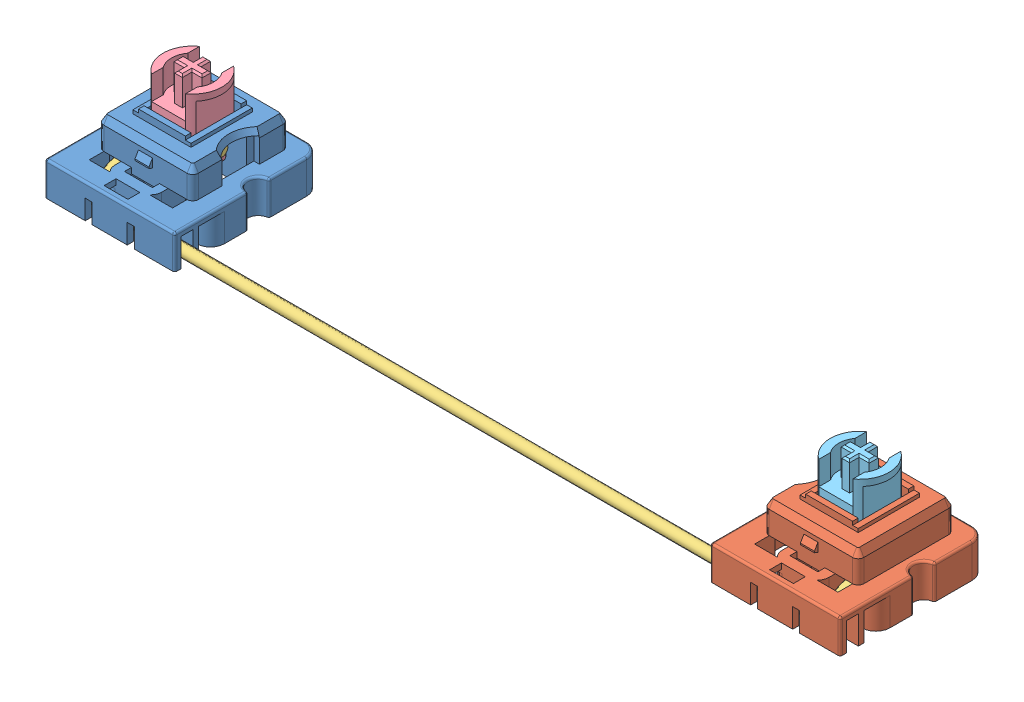
SolidWorks assembly 6u Stabilizers, configuration Default. Lengths in mm.
Overall size (113.55 14.95 20.85).
5 component instances, 5 part files, 12 mates.
Components (placement in the parent):
- 6u Stabilizer Housing Left-1: 6u Stabilizer Housing Left [Default] at (6.8702 11.4991 13.5894) size (18.55 10.05 20.85)
- 6u Stabilizer Housing Right-1: 6u Stabilizer Housing Right [Default] at (101.8702 11.4991 13.5894) size (18.55 10.05 20.85)
- Stabilizer Wire-1: Stabilizer Wire [Default] at (54.3702 9.1991 23.8394) x (1 0 0) z (0 -0.386731 0.922193) size (106 1.6 13.1)
- 6u Stabilizer Plunger Left rev.2-1: 6u Stabilizer Plunger Left rev.2 [Default] at (6.7452 18.4465 13.5894) size (8.4 10.8 6.85)
- 6u Stabilizer Plunger Right rev.2-1: 6u Stabilizer Plunger Right rev.2 [Default] at (101.9952 18.4465 13.5894) size (8.4 10.8 6.85)
Mates (geometry in assembly coordinates):
- Coincident2: coincident: plane of 6u Stabilizer Housing Left-1 through (6.8702 11.4991 13.5894) normal (0 0 1); plane of 6u Stabilizer Housing Right-1 through (101.8702 11.4991 13.5894) normal (0 0 1)
- Coincident3: coincident: plane of 6u Stabilizer Housing Left-1 through (6.8702 11.4991 13.5894) normal (0 1 0); plane of 6u Stabilizer Housing Right-1 through (101.8702 11.4991 13.5894) normal (0 1 0)
- Tangent1: tangent: plane of 6u Stabilizer Housing Left-1 through (6.8702 9.9991 13.5894) normal (0 -1 0); cylinder of Stabilizer Wire-1 through (104.9702 9.1991 23.8394) axis (-1 0 0) radius 0.8
- Tangent2: tangent: plane of 6u Stabilizer Housing Left-1 through (16.1452 -11.0727 24.6394) normal (0 0 -1); cylinder of Stabilizer Wire-1 through (104.9702 9.1991 23.8394) axis (-1 0 0) radius 0.8
- Distance1: distance = 47.5 mm: plane of 6u Stabilizer Housing Left-1 through (6.8702 11.4991 13.5894) normal (1 0 0); plane of Stabilizer Wire-1 through (54.3702 9.1991 23.8394) normal (1 0 0)
- Distance2: distance = 47.5 mm: plane of 6u Stabilizer Housing Right-1 through (101.8702 11.4991 13.5894) normal (1 0 0); plane of Stabilizer Wire-1 through (54.3702 9.1991 23.8394) normal (1 0 0)
- Coincident9: coincident: plane of 6u Stabilizer Housing Left-1 through (6.8702 11.4991 13.5894) normal (1 0 0); plane of 6u Stabilizer Plunger Left rev.2-1 through (6.8702 18.4465 13.5894) normal (1 0 0)
- Coincident11: coincident: plane of 6u Stabilizer Plunger Left rev.2-1 through (6.7452 18.4465 13.5894) normal (0 0 1); plane of 6u Stabilizer Housing Left-1 through (6.8702 11.4991 13.5894) normal (0 0 1)
- Tangent4: tangent: cylinder of Stabilizer Wire-1 through (3.7702 13.6465 13.2342) axis (1 0 0) radius 0.8; plane of 6u Stabilizer Plunger Left rev.2-1 through (6.7452 14.4465 13.5894) normal (0 -1 0)
- Coincident12: coincident: plane of 6u Stabilizer Housing Right-1 through (101.8702 11.4991 13.5894) normal (1 0 0); plane of 6u Stabilizer Plunger Right rev.2-1
- Coincident13: coincident: plane of 6u Stabilizer Housing Right-1 through (101.8702 11.4991 13.5894) normal (0 0 1); plane of 6u Stabilizer Plunger Right rev.2-1
- Tangent5: tangent: cylinder of Stabilizer Wire-1 through (98.1202 13.6465 13.2342) axis (1 0 0) radius 0.8; plane of 6u Stabilizer Plunger Right rev.2-1 through (101.9952 14.4465 13.5894) normal (0 -1 0)
